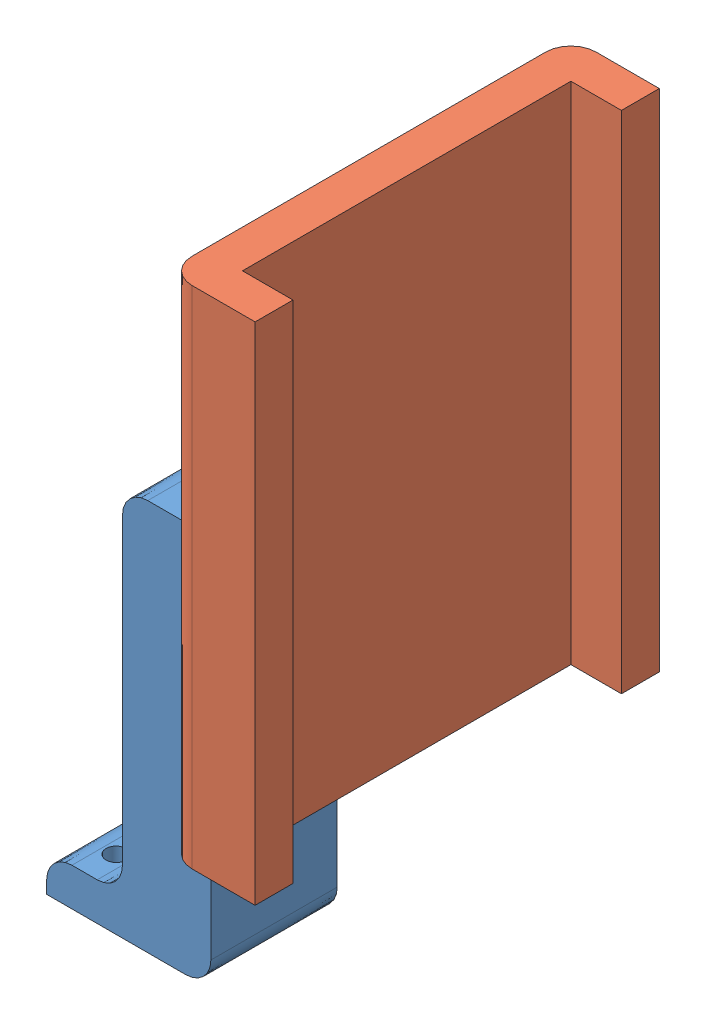
SolidWorks assembly npx_holder_with_leg_6mm, configuration Default. Lengths in mm.
Overall size (6.25 14 8).
2 component instances, 2 part files, 4 mates.
Components (placement in the parent):
- littlel-1: littlel [Default] at (3.5539 4.8106 4.4198) size (4.5 7.75 2.5)
- npx_holder_shaft-1: npx_holder_shaft [Default] at (5.0896 8.0606 4.4198) x (0 0 -1) z (1 0 0) size (8 10 1.75)
Mates (geometry in assembly coordinates):
- Coincident1: coincident: plane of assembly through (0 0 0) normal (0 0 1); plane of littlel-1 through (3.5539 4.8106 4.4198) normal (0 0 1); plane of assembly
- Coincident3: coincident anti-aligned: plane of littlel-1 through (5.0896 4.8106 3.7948) normal (1 0 0); plane of npx_holder_shaft-1 through (5.0896 8.0606 4.4198) normal (-1 0 0)
- Coincident4: coincident anti-aligned: plane of littlel-1 through (3.5539 4.8106 4.4198) normal (0 0 1); plane of npx_holder_shaft-1 through (5.0896 8.0606 4.4198) normal (0 0 -1)
- Distance1: distance = 2 mm: line of littlel-1 through (2.0896 5.0606 4.4198) axis (1 0 0); plane of npx_holder_shaft-1 through (5.8396 3.0606 4.4198) normal (0 -1 0)
